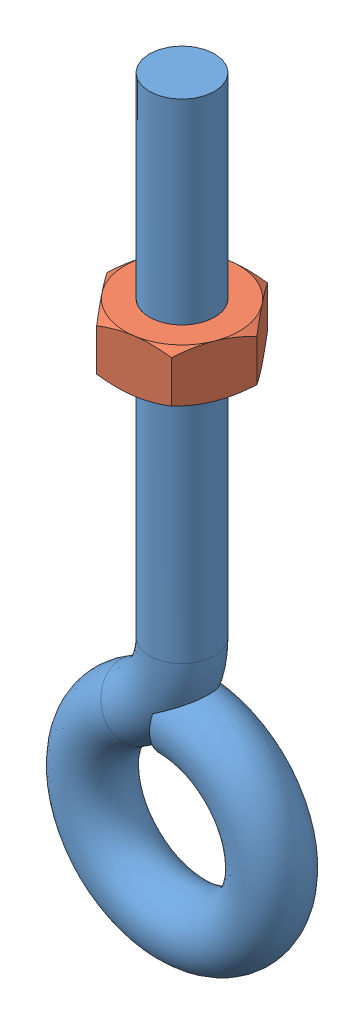
SolidWorks assembly EYE-BOLT+Nut, configuration Standard. Lengths in mm.
Overall size (15 47.03 10.08).
2 component instances, 2 part files, 2 mates.
Components (placement in the parent):
- TURNED-EYE-BOLT-1: TURNED-EYE-BOLT [Standard] at origin size (15 47.03 4)
- hex nut style 1 gradeab_din_a2-1: hex nut style 1 gradeab_din_a2 [Hexagon Nut ISO 4032 - M4 - D - C] at (0 27.5263 0) x (0.930689 0 0.365813) z (0 1 0) size (7 8.08 3.2)
Mates (geometry in assembly coordinates):
- Concentric1: concentric aligned: cylinder of TURNED-EYE-BOLT-1 through (0 9.5263 0) axis (0 1 0) radius 2; cylinder of hex nut style 1 gradeab_din_a2-1 through (0 2.4888 0) axis (0 1 0) radius 2
- Distance1: distance = 12 mm aligned: plane of TURNED-EYE-BOLT-1 through (0 39.5263 0) normal (0 1 0); plane of hex nut style 1 gradeab_din_a2-1 through (-6.5148 27.5263 -2.5607) normal (0 1 0)
